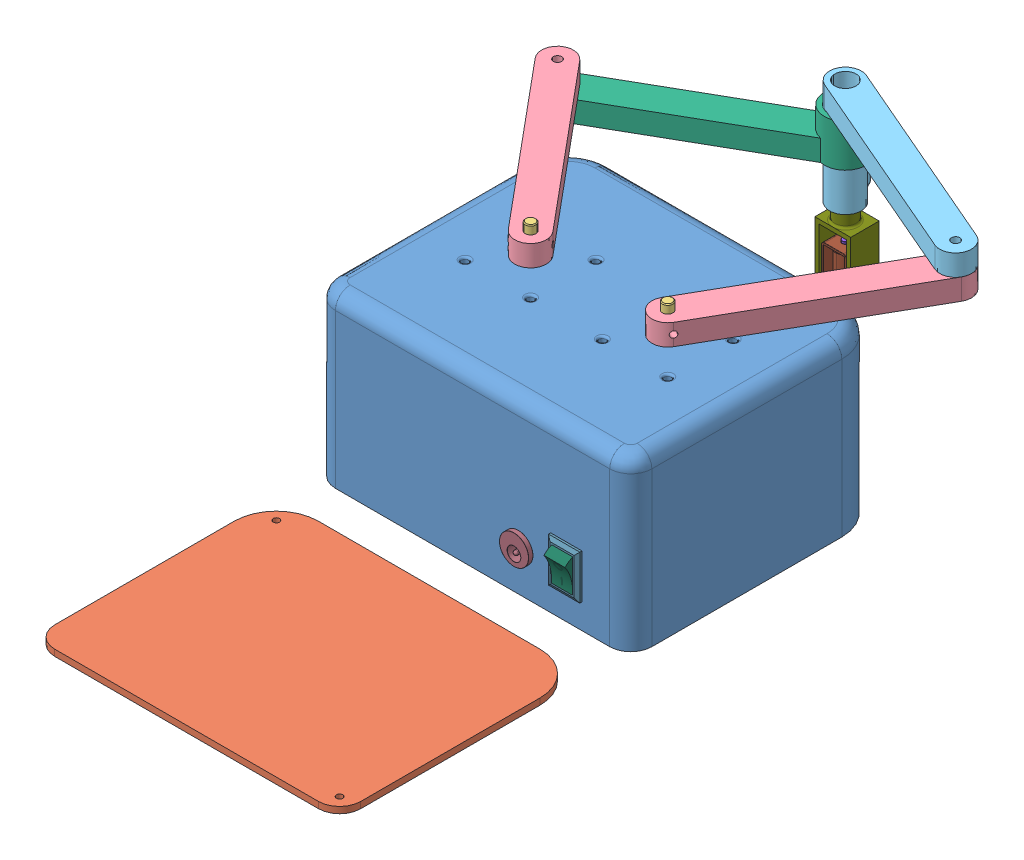
SolidWorks assembly Assem, configuration Default. Lengths in mm.
Overall size (200.94 102 335.59).
21 component instances, 16 part files, 33 mates.
Components (placement in the parent):
- base-1: base [Default] at (106.5 27.1593 136.4053) size (150 80 120)
- disk-1: disk [Default] at (106.5 27.1593 274.3914) size (145 3 115)
- NEMA 17 1.2A 0.2Nm 1.8° v3-1: NEMA 17 1.2A 0.2Nm 1.8° v3 [Default] at (74 72.3593 136.4053) x (0 1 0) z (-0.999999 0 0.00146) size (52.8 42.83 42.35)
- NEMA 17 1.2A 0.2Nm 1.8° v3-2: NEMA 17 1.2A 0.2Nm 1.8° v3 [Default] at (139 72.3593 136.4053) x (0 1 0) z (-0.999999 0 0.00146) size (52.8 42.83 42.35)
- bicep-1: bicep [Default] at (139 109.1593 136.4053) x (0.495827 0 -0.868421) z (0.868421 0 0.495827) size (115 10 15)
- bicep-2: bicep [Default] at (74 109.1593 136.4053) x (-0.640406 0 -0.768036) z (0.768036 0 -0.640406) size (115 10 15)
- forecep_right-1: forecep_right [Default] at (96.7628 119.1593 9.9512) x (0.918199 0 0.396119) z (-0.396119 0 0.918199) size (117.49 50 17.49)
- forecep_left-1: forecep_left [Default] at (9.9594 99.1593 59.6017) x (0.868034 0 -0.496504) z (0.496504 0 0.868034) size (117.5 20 20)
- Keyestudio CNC Shield Arduino Nano-1: Keyestudio CNC Shield Arduino Nano [Default] at (71.875 70.4093 186.9053) x (-1 0 0) z (0 -1 0) size (71.75 12.6 58.5)
- Solenoid.STEP-1: Solenoid.STEP [Default] at (102.2628 41.7973 14.9512) x (0 1 0) z (0 0 -1) size (29 12 11)
  - Shaft Assem.STEP-1: Shaft Assem.STEP [Default] at (2.5 -6 5.5) x (0 0.575247 0.81798) z (1 0 0) size (7.1 6.75 29)
    - Shaft.STEP-1: Shaft.STEP [Default] at origin size (4 4 29)
    - Circlip.STEP-1: Circlip.STEP [Default] at (0 0 -8.45) size (7.1 5.79 0.6)
    - Spring.STEP-1: Spring.STEP [Default] at (0 0 -2.3) x (-1 0 0) z (0 0 -1) size (6.28 6.48 5.72)
  - Shell.STEP-1: Shell.STEP [Default] at origin size (20.5 12 11)
- ARDUINO NANO-1: ARDUINO NANO [Default] at (63.25 76.7893 172.6553) x (0 1 0) z (-1 0 0) size (18 19.4 44.8)
- DC Coax Panel Mount Power Jack (PN 601)-1: DC Coax Panel Mount Power Jack (PN 601) [default] at (128.2373 46.3921 196.4053) size (13.8 13.8 18.1)
- Switch Montaj-1: Switch Montaj [Varsayılan] at (150.8539 50.7648 162.2053) x (0 1 0) z (0 0 1) size (21.23 14.85 25.41)
  - Switch-1: Switch [Varsayılan] at (-10.7432 -5.856 23) size (21.23 14.85 21.45)
  - Switch Açma Kapama-2: Switch Açma Kapama [Varsayılan] at (-0.3897 4.944 31.6284) x (0.965926 0 0.258819) z (0 -1 0) size (16.31 8 10)
- solenoidHolder-1: solenoidHolder [Default] at (96.7628 55.7973 9.9512) x (-1 0 0) z (0 0 -1) size (17 67 13.5)
Mates (geometry in assembly coordinates):
- Coincident7: coincident aligned: plane of NEMA 17 1.2A 0.2Nm 1.8° v3-1 through (74 97.1593 157.5553) normal (0 0 1); plane of NEMA 17 1.2A 0.2Nm 1.8° v3-2 through (139 97.1593 157.5553) normal (0 0 1)
- Concentric13: concentric anti-aligned: cylinder of NEMA 17 1.2A 0.2Nm 1.8° v3-2 through (139 108.6593 136.4053) axis (0 1 0) radius 2.5; cylinder of bicep-1 through (139 119.1593 136.4053) axis (0 -1 0) radius 2.5
- Distance3: distance = 4 mm aligned: plane of bicep-1 through (139 119.1593 136.4053) normal (0 1 0); plane of NEMA 17 1.2A 0.2Nm 1.8° v3-2 through (139 123.1593 136.4053) normal (0 1 0)
- Concentric14: concentric anti-aligned: cylinder of NEMA 17 1.2A 0.2Nm 1.8° v3-1 through (74 108.6593 136.4053) axis (0 1 0) radius 2.5; cylinder of bicep-2 through (74 119.1593 136.4053) axis (0 -1 0) radius 2.5
- Distance4: distance = 4 mm aligned: plane of bicep-2 through (74 119.1593 136.4053) normal (0 1 0); plane of NEMA 17 1.2A 0.2Nm 1.8° v3-1 through (74 123.1593 136.4053) normal (0 1 0)
- Concentric21: concentric aligned: cylinder of bicep-1 through (188.5827 119.1593 49.5632) axis (0 -1 0) radius 2; cylinder of forecep_right-1 through (188.5827 129.1593 49.5632) axis (0 -1 0) radius 2
- Coincident14: coincident anti-aligned: plane of bicep-2 through (74 109.1593 136.4053) normal (0 -1 0); plane of forecep_left-1 through (9.9594 109.1593 59.6017) normal (0 1 0)
- Concentric23: concentric aligned: cylinder of bicep-2 through (9.9594 119.1593 59.6017) axis (0 -1 0) radius 2; cylinder of forecep_left-1 through (9.9594 109.1593 59.6017) axis (0 -1 0) radius 2
- Coincident31: coincident anti-aligned: plane of bicep-1 through (139 119.1593 136.4053) normal (0 1 0); plane of forecep_right-1 through (96.7628 119.1593 9.9512) normal (0 -1 0)
- Concentric26: concentric aligned: cylinder of forecep_right-1 through (96.7628 129.1593 9.9512) axis (0 1 0) radius 7.5; cylinder of forecep_left-1 through (96.7628 99.1583 9.9512) axis (0 1 0) radius 7.75
- Coincident34: coincident anti-aligned: plane of base-1 through (34 107.1593 76.4053) normal (1 0 0); plane of disk-1 through (34 30.1593 216.8914) normal (-1 0 0)
- Coincident35: coincident anti-aligned: plane of Keyestudio CNC Shield Arduino Nano-1 through (71.875 70.4093 176.8053) normal (0 0 -1); plane of ARDUINO NANO-1 through (63.25 76.7893 176.8053) normal (0 0 1)
- Width1: width aligned: plane of ARDUINO NANO-1 through (82.3 83.1593 176.8053) normal (1 0 0); plane of ARDUINO NANO-1 through (44.2 83.1593 176.8053) normal (-1 0 0); plane of Keyestudio CNC Shield Arduino Nano-1 through (82.5 85.6593 176.8053) normal (1 0 0); plane of Keyestudio CNC Shield Arduino Nano-1 through (44 85.6593 176.8053) normal (-1 0 0)
- Width2: width anti-aligned: plane of ARDUINO NANO-1 through (44.2 85.6593 176.8053) normal (0 1 0); plane of ARDUINO NANO-1 through (44.2 83.1593 176.8053) normal (0 -1 0); plane of Keyestudio CNC Shield Arduino Nano-1 through (82.5 83.1593 176.8053) normal (0 -1 0); plane of Keyestudio CNC Shield Arduino Nano-1 through (82.5 85.6593 176.8053) normal (0 1 0)
- Coincident36: coincident aligned: plane of NEMA 17 1.2A 0.2Nm 1.8° v3-1 through (74 101.1593 136.4053) normal (0 1 0); plane of NEMA 17 1.2A 0.2Nm 1.8° v3-2 through (139 101.1593 136.4053) normal (0 1 0)
- Coincident37: coincident anti-aligned: plane of base-1 through (106.5 101.1593 136.4053) normal (0 -1 0); plane of NEMA 17 1.2A 0.2Nm 1.8° v3-2 through (139 101.1593 136.4053) normal (0 1 0)
- Concentric27: concentric aligned: cylinder of base-1 through (139 27.1583 136.4053) axis (0 1 0) radius 3.25; cylinder of NEMA 17 1.2A 0.2Nm 1.8° v3-2 through (139 108.6593 136.4053) axis (0 1 0) radius 2.5
- Concentric28: concentric aligned: cylinder of base-1 through (74 27.1583 136.4053) axis (0 1 0) radius 3.25; cylinder of NEMA 17 1.2A 0.2Nm 1.8° v3-1 through (74 108.6593 136.4053) axis (0 1 0) radius 2.5
- Coincident38: coincident anti-aligned: plane of base-1 through (36 97.1593 186.9053) normal (0 0 -1); plane of Keyestudio CNC Shield Arduino Nano-1 through (71.875 70.4093 186.9053) normal (0 0 1)
- Coincident39: coincident anti-aligned: plane of base-1 through (36 97.1593 184.4053) normal (1 0 0); plane of Keyestudio CNC Shield Arduino Nano-1 through (36 41.1593 185.3053) normal (-1 0 0)
- Coincident42: coincident anti-aligned: plane of base-1 through (106.5 97.1593 136.4053) normal (0 -1 0); plane of Keyestudio CNC Shield Arduino Nano-1 through (44 97.1593 182.8053) normal (0 1 0)
- Concentric29: concentric anti-aligned: cylinder of base-1 through (128.2373 46.3921 76.4043) axis (0 0 1) radius 6.15; cylinder of DC Coax Panel Mount Power Jack (PN 601)-1 through (128.2373 46.3921 198.5053) axis (0 0 -1) radius 6.9
- Coincident43: coincident anti-aligned: plane of base-1 through (31.5 107.1593 196.4053) normal (0 0 1); plane of DC Coax Panel Mount Power Jack (PN 601)-1 through (128.2373 46.3921 196.4053) normal (0 0 -1)
- Width3: width anti-aligned: plane of Switch Montaj-1/Switch-1 through (145.1099 40.0217 187.4053) normal (-1 0 0); plane of base-1 through (156.7099 40.0217 187.4053) normal (1 0 0); plane of Switch Montaj-1/Switch-1 through (144.1599 59.4217 76.4043) normal (1 0 0); plane of base-1 through (157.6599 59.4217 76.4043) normal (-1 0 0)
- Width4: width anti-aligned: plane of Switch Montaj-1/Switch-1 through (145.1099 58.6217 196.4053) normal (0 1 0); plane of base-1 through (145.1099 40.2217 196.4053) normal (0 -1 0); plane of Switch Montaj-1/Switch-1 through (144.1599 59.4217 76.4043) normal (0 -1 0); plane of base-1 through (144.1599 39.4217 76.4043) normal (0 1 0)
- Coincident44: coincident anti-aligned: plane of base-1 through (31.5 107.1593 196.4053) normal (0 0 1); plane of Switch Montaj-1/Switch-1 through (156.7099 40.0217 196.4053) normal (0 0 -1)
- Coincident45: coincident anti-aligned: plane of base-1 through (159 30.1593 98.9053) normal (0 -1 0); plane of disk-1 through (106.5 30.1593 274.3914) normal (0 1 0)
- Coincident46: coincident anti-aligned: plane of base-1 through (31.5 107.1593 193.9053) normal (0 0 -1); plane of disk-1 through (34 30.1593 193.9053) normal (0 0 1)
- Coincident47: coincident anti-aligned: plane of Solenoid.STEP-1/Shell.STEP-1 through (90.2628 62.2973 3.9512) normal (-1 0 0); plane of solenoidHolder-1 through (90.2628 41.7973 3.9512) normal (1 0 0)
- Coincident48: coincident anti-aligned: plane of Solenoid.STEP-1/Shell.STEP-1 through (91.2628 41.7973 3.9512) normal (0 -1 0); plane of solenoidHolder-1 through (92.2628 41.7973 3.9512) normal (0 1 0)
- Coincident49: coincident anti-aligned: plane of Solenoid.STEP-1/Shell.STEP-1 through (102.2628 41.7973 3.9512) normal (0 0 -1); plane of solenoidHolder-1 through (96.7628 55.7973 3.9512) normal (0 0 1)
- Concentric30: concentric anti-aligned: cylinder of forecep_right-1 through (96.7628 79.1583 9.9512) axis (0 1 0) radius 5; cylinder of solenoidHolder-1 through (96.7628 106.7973 9.9512) axis (0 -1 0) radius 5
- Parallel1: parallel aligned: plane of base-1 through (31.5 107.1593 76.4053) normal (0 0 -1); plane of solenoidHolder-1 through (96.7628 55.7973 2.4512) normal (0 0 -1)
